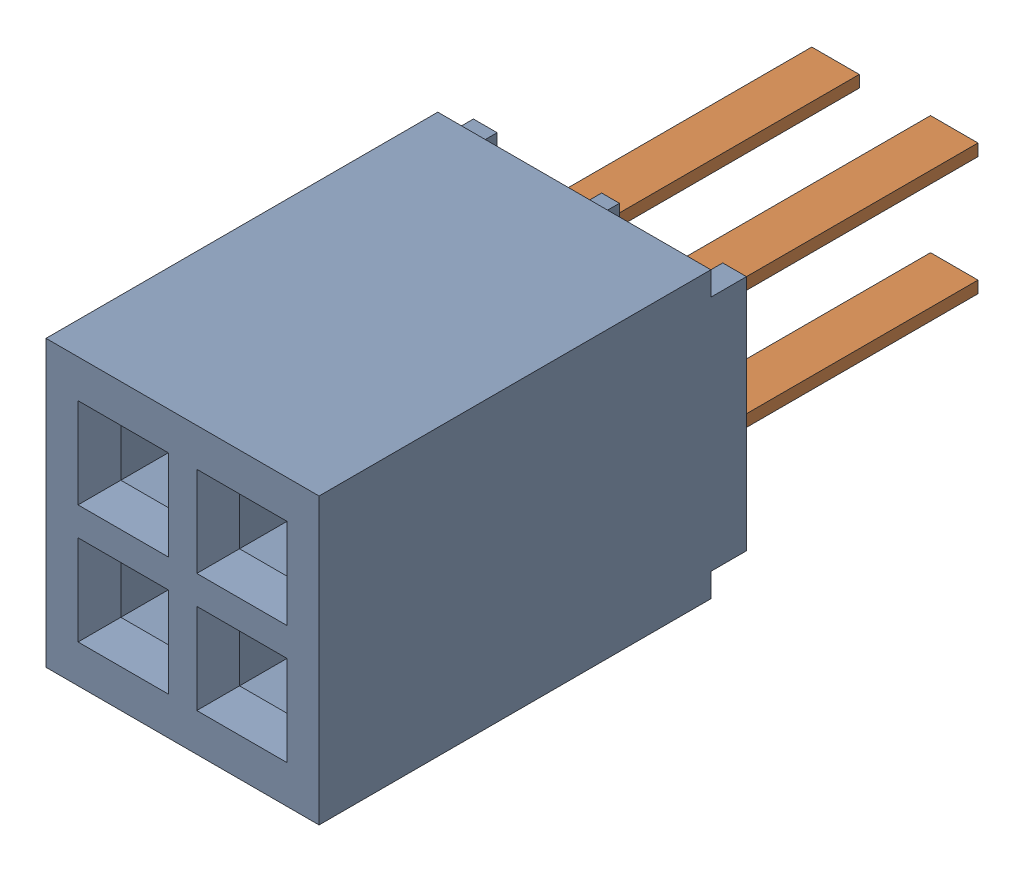
SolidWorks assembly J2, configuration ﾃﾞﾌｫﾙﾄ. Lengths in mm.
Overall size (2.92 3.05 7.62).
3 component instances, 2 part files, 0 mates.
Components (placement in the parent):
- SFMC-102-01-L-D-1: SFMC-102-01-L-D [ﾃﾞﾌｫﾙﾄ] at (18.535 40.97 0) x (-1 0 0) z (0 1 0) size (2.92 7.62 3.05)
  - _SFMC-102-01_socket-1: _SFMC-102-01_socket [ﾃﾞﾌｫﾙﾄ] at origin size (2.92 4.57 3.05)
  - _C-02-01_spins-1: _C-02-01_spins [ﾃﾞﾌｫﾙﾄ] at origin size (1.78 3.81 1.78)
